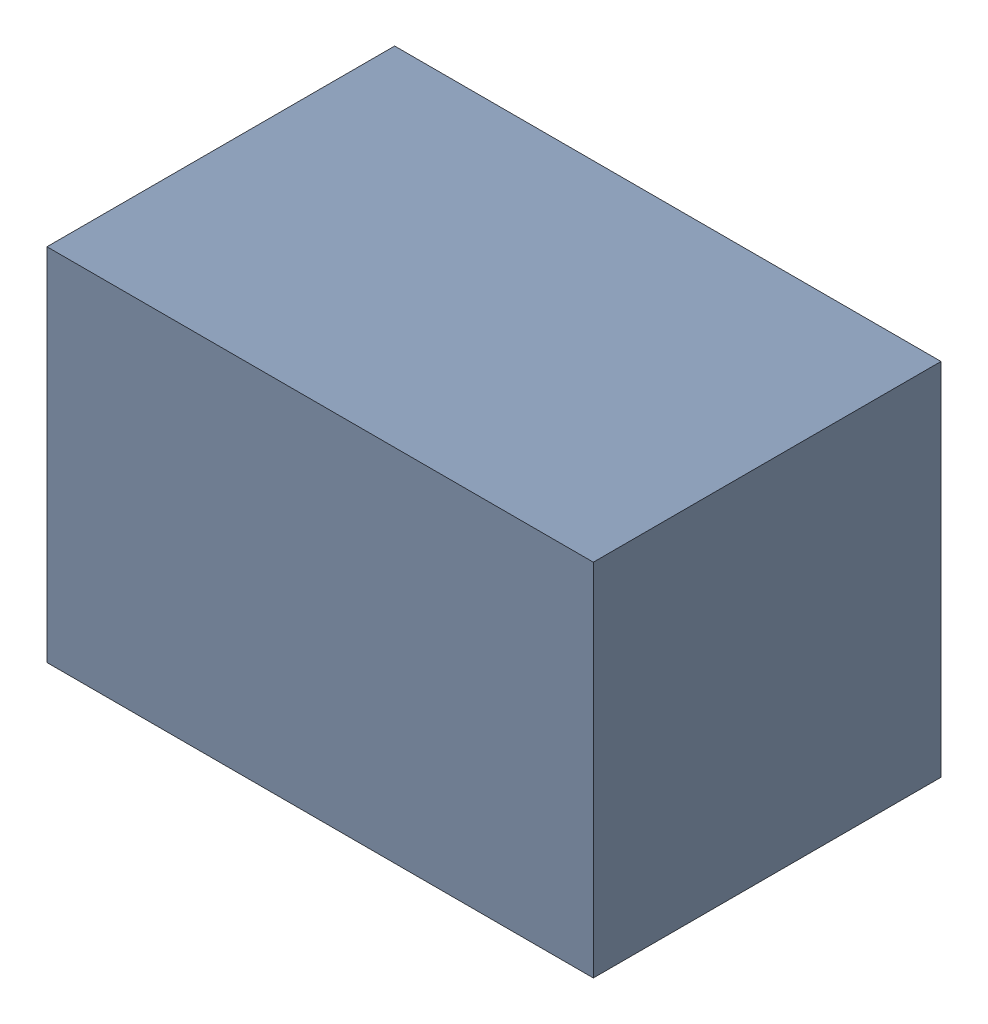
SolidWorks assembly C25, configuration Default. Lengths in mm.
Overall size (2.2 1.45 1.4).
2 component instances, 1 part files, 0 mates.
Components (placement in the parent):
- 1017092848-1: 1017092848 [Default] at (152.4 144.78 0) size (2.2 1.45 1.4)
  - Extruded_3-1: Extruded_3 [Default] at origin size (2.2 1.45 1.4)
